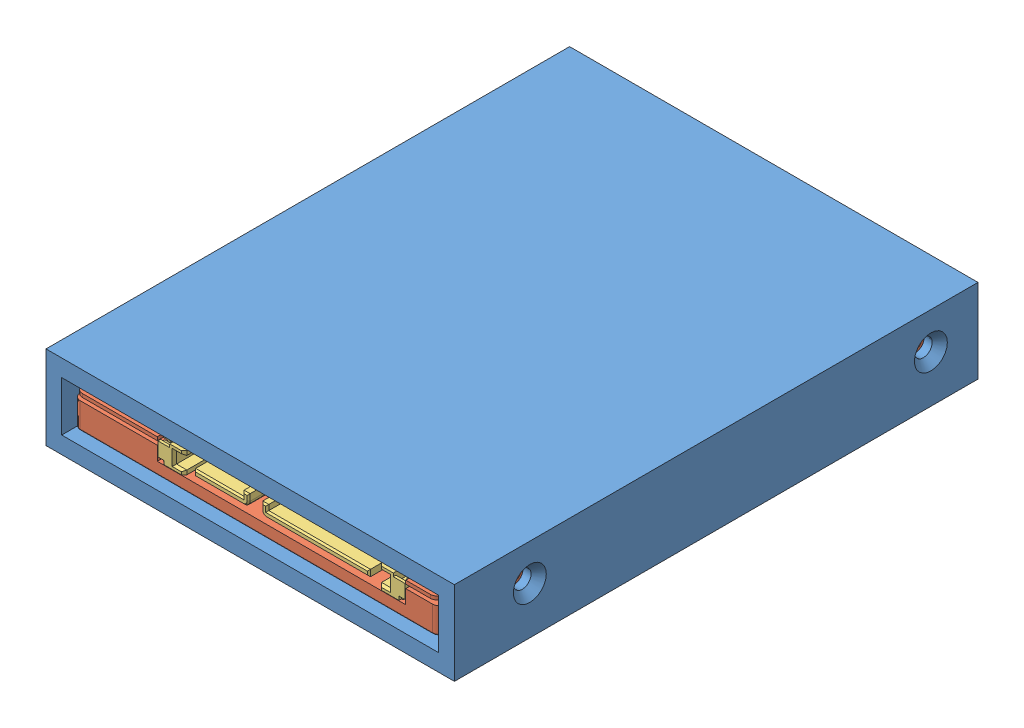
SolidWorks assembly 2.5HDD_With_Support, configuration Défaut. Lengths in mm.
Overall size (78 16 101.25).
10 component instances, 4 part files, 3 mates.
Components (placement in the parent):
- Support2.5_HDD-1: Support2.5_HDD [Défaut] at (-39.5512 -9.5476 50) size (78 16 100)
- 2.5 HDD-1: 2.5 HDD [Default] at (0.5238 2.4524 99.7985) x (-1 0 0) z (0 0 1) size (71.75 11.67 101.15)
  - 2.5 HDD-1: 2.5 HDD [Default] at origin size (71.75 11.67 101.15)
  - hdd sata-1: hdd sata [Default] at (31.2138 40.3899 44.1015) x (-1 0 0) z (0 0 1) size (50.93 4 8.5)
  - cross recessed pan head screws gb-1: cross recessed pan head screws gb [GB_CROSS_SCREWS_TYPE1 M1.6X3-3  H type-N] at (-32.385 11.6124 -7.7343) x (0 -1 0) z (0.546944 0 -0.837169) size (4.29 3.2 3.2)
  - cross recessed pan head screws gb-2: cross recessed pan head screws gb [GB_CROSS_SCREWS_TYPE1 M1.6X3-3  H type-N] at (-25.908 11.6124 36.0807) x (0 -1 0) z (-0.546944 0 0.837169) size (4.29 3.2 3.2)
  - cross recessed pan head screws gb-3: cross recessed pan head screws gb [GB_CROSS_SCREWS_TYPE1 M1.6X3-3  H type-N] at (-32.385 11.6124 -47.5615) x (0 -1 0) z (-0.546944 0 0.837169) size (4.29 3.2 3.2)
  - cross recessed pan head screws gb-4: cross recessed pan head screws gb [GB_CROSS_SCREWS_TYPE1 M1.6X3-3  H type-N] at (32.385 11.6124 -47.5615) x (0 -1 0) z (0.546944 0 -0.837169) size (4.29 3.2 3.2)
  - cross recessed pan head screws gb-5: cross recessed pan head screws gb [GB_CROSS_SCREWS_TYPE1 M1.6X3-3  H type-N] at (32.385 11.6124 -7.7343) x (0 -1 0) z (-0.546944 0 0.837169) size (4.29 3.2 3.2)
  - cross recessed pan head screws gb-6: cross recessed pan head screws gb [GB_CROSS_SCREWS_TYPE1 M1.6X3-3  H type-N] at (32.385 11.6124 41.8465) x (0 -1 0) z (-0.546944 0 0.837169) size (4.29 3.2 3.2)
Mates (geometry in assembly coordinates):
- Coaxiale1: concentric anti-aligned: cylinder of Support2.5_HDD-1 through (-39.5512 -0.5476 135.6) axis (-1 0 0) radius 1.7; cylinder of 2.5 HDD-1/2.5 HDD-1 through (35.4488 -0.5476 135.6) axis (1 0 0) radius 1.25
- Coaxiale5: concentric aligned: circle of Support2.5_HDD-1; circle of 2.5 HDD-1/2.5 HDD-1
- Coïncidente1: coincident anti-aligned: plane of Support2.5_HDD-1 through (35.4488 3.2024 150) normal (-1 0 0); plane of 2.5 HDD-1/2.5 HDD-1 through (35.4488 -3.8976 49.697) normal (1 0 0)
